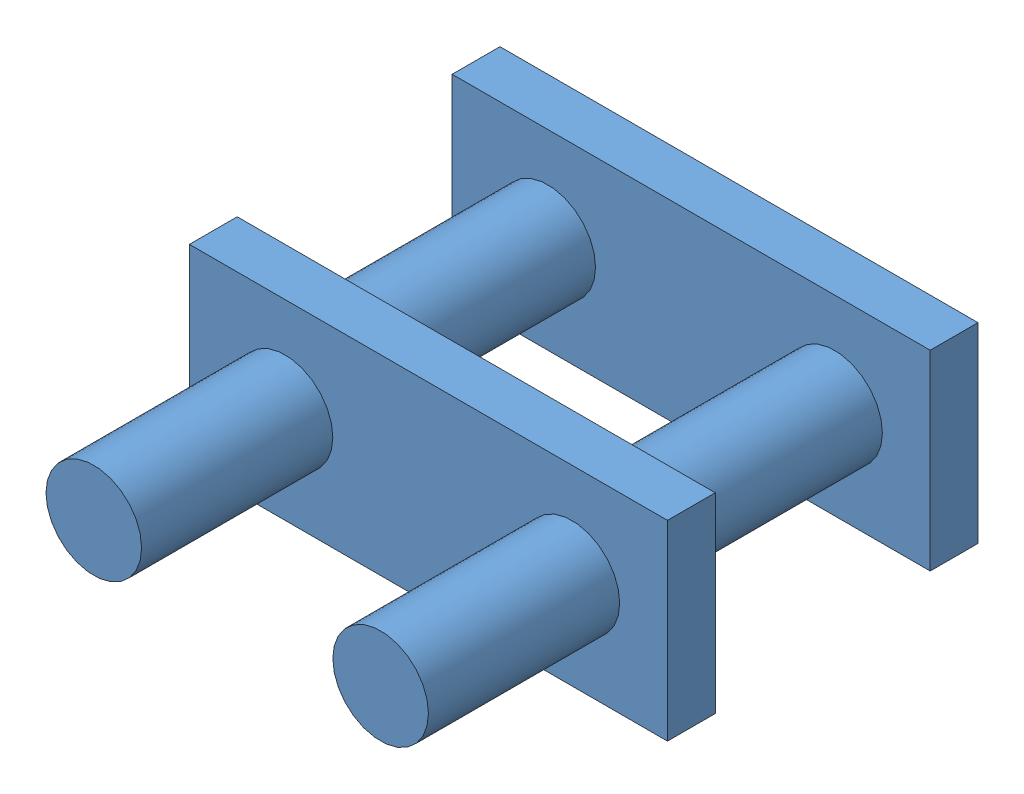
SolidWorks assembly Assemblage1, configuration Défaut. Lengths in mm.
Overall size (51.96 20.29 54.44).
2 component instances, 1 part files, 0 mates.
Components (placement in the parent):
- piece3_TD-1: piece3_TD [Défaut] at (8.3714 1.3366 37.5) size (50 20 25)
- piece3_TD-2: piece3_TD [Défaut] at (10.3317 1.6292 66.9401) size (50 20 25)
